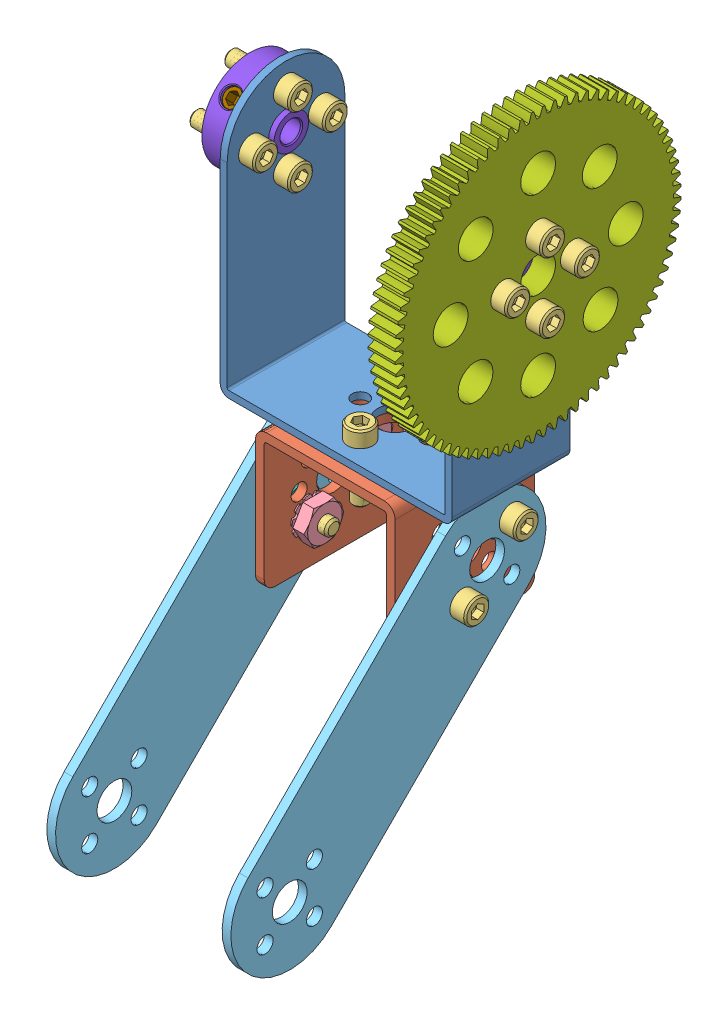
SolidWorks assembly Mantis step 13, configuration Default. Lengths in mm.
Overall size (74.01 159.73 97.13).
33 component instances, 9 part files, 97 mates.
Components (placement in the parent):
- Bracket servo_pivot_multi-1: Bracket servo_pivot_multi [Default] at origin size (53.2 60.1 27)
- Channel 32mm-1: Channel 32mm [Default] x (-1 0 0) z (0 0 1) size (32 32 32)
- Screw SHCS 6-32 x 0.5-1: Screw SHCS 6-32 x 0.5 [PreviewCfg] at (0 5.1052 8) x (0 -1 0) z (0 0 -1) size (16.21 5.74 5.74)
- Screw SHCS 6-32 x 0.5-2: Screw SHCS 6-32 x 0.5 [PreviewCfg] at (0 5.1052 -8) x (0 -1 0) z (0 0 -1) size (16.21 5.74 5.74)
- Nut Hex 6-32 KEP lock-1: Nut Hex 6-32 KEP lock [90675A007] at (0 -4.1828 8) x (-1 0 0) z (0 0 1) size (8.74 3.59 9.17)
- Nut Hex 6-32 KEP lock-2: Nut Hex 6-32 KEP lock [90675A007] at (0 -4.1828 -8) x (-1 0 0) z (0 0 1) size (8.74 3.59 9.17)
- Bracket flat-1: Bracket flat [Default] at (20.1 -38.6274 22.6274) x (0 0.707107 -0.707107) z (0 0.707107 0.707107) size (91 2 27)
- Bracket flat-2: Bracket flat [Default] at (-20.1 -38.6274 22.6274) x (0 0.707107 -0.707107) z (0 0.707107 0.707107) size (91 2 27)
- Nylon spacer small-1: Nylon spacer small [Default] at (19.1 -21.6569 5.6569) x (0 -1 0) z (1 0 0) size (9.5 9.5 3.1)
- Nylon spacer small-2: Nylon spacer small [Default] at (19.1 -10.3431 -5.6569) x (0 1 0) z (1 0 0) size (9.5 9.5 3.1)
- Nylon spacer small-3: Nylon spacer small [Default] at (-16 -10.3431 -5.6569) x (0 1 0) z (1 0 0) size (9.5 9.5 3.1)
- Nylon spacer small-4: Nylon spacer small [Default] at (-16 -21.6569 5.6569) x (0 1 0) z (1 0 0) size (9.5 9.5 3.1)
- Screw SHCS 6-32 x 0.5-3: Screw SHCS 6-32 x 0.5 [PreviewCfg] at (24.6052 -10.3431 -5.6569) x (-1 0 0) z (0 0 1) size (16.21 5.74 5.74)
- Screw SHCS 6-32 x 0.5-4: Screw SHCS 6-32 x 0.5 [PreviewCfg] at (24.6052 -21.6569 5.6569) x (-1 0 0) z (0 0 -1) size (16.21 5.74 5.74)
- Screw SHCS 6-32 x 0.5-5: Screw SHCS 6-32 x 0.5 [PreviewCfg] at (-24.6052 -10.3431 -5.6569) x (1 0 0) z (0 0 -1) size (16.21 5.74 5.74)
- Screw SHCS 6-32 x 0.5-6: Screw SHCS 6-32 x 0.5 [PreviewCfg] at (-24.6052 -21.6569 5.6569) size (16.21 5.74 5.74)
- Nut Hex 6-32 KEP lock-3: Nut Hex 6-32 KEP lock [90675A007] at (11.8172 -10.3431 -5.6569) x (0 1 0) z (0 0 1) size (8.74 3.59 9.17)
- Nut Hex 6-32 KEP lock-4: Nut Hex 6-32 KEP lock [90675A007] at (11.8172 -21.6569 5.6569) x (0 1 0) z (0 0 1) size (8.74 3.59 9.17)
- Nut Hex 6-32 KEP lock-5: Nut Hex 6-32 KEP lock [90675A007] at (-11.8172 -21.6569 5.6569) x (0 -1 0) z (0 0 1) size (8.74 3.59 9.17)
- Nut Hex 6-32 KEP lock-6: Nut Hex 6-32 KEP lock [90675A007] at (-11.8172 -10.3431 -5.6569) x (0 -1 0) z (0 0 1) size (8.74 3.59 9.17)
- Gear Metric 80T-1: Gear Metric 80T [PreviewCfg] at (26.6 46.6 0) size (6.2 65.57 65.57)
- Hub axle shaft-1: Hub axle shaft [Default] at (25 46.6 0) x (0 0 -1) z (1 0 0) size (22 22 9.5)
- Hub axle shaft-2: Hub axle shaft [Default] at (-26.6 46.6 0) x (0 0 -1) z (1 0 0) size (22 22 9.5)
- Screw SHCS 6-32 x 0.5-7: Screw SHCS 6-32 x 0.5 [PreviewCfg] at (-21.4948 54.6 0) x (-1 0 0) z (0 1 0) size (16.21 5.74 5.74)
- Screw SHCS 6-32 x 0.5-8: Screw SHCS 6-32 x 0.5 [PreviewCfg] at (-21.4948 46.6 -8) x (-1 0 0) z (0 1 0) size (16.21 5.74 5.74)
- Screw SHCS 6-32 x 0.5-9: Screw SHCS 6-32 x 0.5 [PreviewCfg] at (-21.4948 38.6 0) x (-1 0 0) z (0 1 0) size (16.21 5.74 5.74)
- Screw SHCS 6-32 x 0.5-10: Screw SHCS 6-32 x 0.5 [PreviewCfg] at (-21.4948 46.6 8) x (-1 0 0) z (0 1 0) size (16.21 5.74 5.74)
- Screw SHCS 6-32 x 0.5-13: Screw SHCS 6-32 x 0.5 [PreviewCfg] at (36.3052 54.6 0) x (-1 0 0) z (0 -1 0) size (16.21 5.74 5.74)
- Screw SHCS 6-32 x 0.5-14: Screw SHCS 6-32 x 0.5 [PreviewCfg] at (36.3052 46.6 8) x (-1 0 0) z (0 -1 0) size (16.21 5.74 5.74)
- Screw SHCS 6-32 x 0.5-15: Screw SHCS 6-32 x 0.5 [PreviewCfg] at (36.3052 38.6 0) x (-1 0 0) z (0 -1 0) size (16.21 5.74 5.74)
- Screw SHCS 6-32 x 0.5-16: Screw SHCS 6-32 x 0.5 [PreviewCfg] at (36.3052 46.6 -8) x (-1 0 0) z (0 -1 0) size (16.21 5.74 5.74)
- Screw SET 10-32 x 0.3125-1: Screw SET 10-32 x 0.3125 [PreviewCfg] at (-29.9516 53.8687 7.2793) x (0 -0.706591 -0.707622) z (0 0.707622 -0.706591) size (7.94 4.83 4.83)
- Screw SET 10-32 x 0.3125-2: Screw SET 10-32 x 0.3125 [PreviewCfg] at (21.6484 53.8687 7.2793) x (0 -0.706591 -0.707622) z (0 -0.707622 0.706591) size (7.94 4.83 4.83)
Mates (geometry in assembly coordinates):
- Coincident38: coincident anti-aligned: plane of Bracket servo_pivot_multi-1 through (-24.6 0 -13.5) normal (0 -1 0); plane of Channel 32mm-1 through (13.5 0 16) normal (0 1 0)
- Coincident39: coincident aligned: plane of Channel 32mm-1 through (0 0 0) normal (0 0 1); plane of assembly through (0 0 0) normal (0 0 1)
- Coincident40: coincident anti-aligned: plane of Channel 32mm-1; plane of assembly through (0 0 0) normal (1 0 0)
- Concentric7: concentric anti-aligned: cylinder of Screw SHCS 6-32 x 0.5-2 through (0 36.8552 -8) axis (0 1 0) radius 1.7526; cylinder of Bracket servo_pivot_multi-1 through (0 27 -8) axis (0 -1 0) radius 1.85
- Concentric8: concentric anti-aligned: cylinder of Screw SHCS 6-32 x 0.5-1 through (0 36.8552 8) axis (0 1 0) radius 1.7526; cylinder of Bracket servo_pivot_multi-1 through (0 27 8) axis (0 -1 0) radius 1.85
- Coincident4: coincident anti-aligned: plane of Bracket servo_pivot_multi-1 through (24.6 1.6 -13.5) normal (0 1 0); plane of Screw SHCS 6-32 x 0.5-2 through (-2.8702 1.6 -8) normal (0 -1 0)
- Coincident5: coincident anti-aligned: plane of Bracket servo_pivot_multi-1 through (24.6 1.6 -13.5) normal (0 1 0); plane of Screw SHCS 6-32 x 0.5-1 through (-2.8702 1.6 8) normal (0 -1 0)
- Concentric9: concentric anti-aligned: circle of Nut Hex 6-32 KEP lock-1; cylinder of Screw SHCS 6-32 x 0.5-1 through (0 36.8552 8) axis (0 1 0) radius 1.7526
- Concentric10: concentric anti-aligned: circle of Nut Hex 6-32 KEP lock-2; cylinder of Screw SHCS 6-32 x 0.5-2 through (0 36.8552 -8) axis (0 1 0) radius 1.7526
- Concentric30: concentric aligned: cylinder of Screw SHCS 6-32 x 0.5-7 through (10.2552 54.6 0) axis (1 0 0) radius 1.7526; cylinder of Hub axle shaft-2 through (-26.6 54.6 0) axis (1 0 0) radius 1.3526
- Concentric31: concentric aligned: cylinder of Screw SHCS 6-32 x 0.5-8 through (10.2552 46.6 -8) axis (1 0 0) radius 1.7526; cylinder of Hub axle shaft-2 through (-26.6 46.6 -8) axis (1 0 0) radius 1.3526
- Concentric32: concentric aligned: cylinder of Screw SHCS 6-32 x 0.5-10 through (10.2552 46.6 8) axis (1 0 0) radius 1.7526; cylinder of Hub axle shaft-2 through (-26.6 46.6 8) axis (1 0 0) radius 1.3526
- Concentric33: concentric aligned: cylinder of Screw SHCS 6-32 x 0.5-9 through (10.2552 38.6 0) axis (1 0 0) radius 1.7526; cylinder of Hub axle shaft-2 through (-26.6 38.6 0) axis (1 0 0) radius 1.3526
- Coincident24: coincident anti-aligned: plane of Bracket servo_pivot_multi-1 through (-25 2 -13.5) normal (1 0 0); plane of Screw SHCS 6-32 x 0.5-10 through (-25 46.6 10.8702) normal (-1 0 0)
- Coincident25: coincident anti-aligned: plane of Bracket servo_pivot_multi-1 through (-25 2 -13.5) normal (1 0 0); plane of Screw SHCS 6-32 x 0.5-9 through (-25 38.6 2.8702) normal (-1 0 0)
- Coincident26: coincident anti-aligned: plane of Bracket servo_pivot_multi-1 through (-25 2 -13.5) normal (1 0 0); plane of Screw SHCS 6-32 x 0.5-8 through (-25 46.6 -5.1298) normal (-1 0 0)
- Coincident27: coincident anti-aligned: plane of Bracket servo_pivot_multi-1 through (-25 2 -13.5) normal (1 0 0); plane of Screw SHCS 6-32 x 0.5-7 through (-25 54.6 2.8702) normal (-1 0 0)
- Concentric66: concentric aligned: cylinder of Gear Metric 80T-1 through (76.6001 46.6 0) axis (-1 0 0) radius 4; cylinder of Hub axle shaft-1 through (27.8 46.6 0) axis (-1 0 0) radius 3.9624
- Coincident28: coincident anti-aligned: plane of Bracket servo_pivot_multi-1 through (26.6 2 -13.5) normal (1 0 0); plane of Gear Metric 80T-1 through (26.6 46.6 0) normal (-1 0 0)
- Concentric38: concentric aligned: cylinder of Gear Metric 80T-1 through (26.6 46.6 -8) axis (1 0 0) radius 1.75; cylinder of Screw SHCS 6-32 x 0.5-16 through (68.0552 46.6 -8) axis (1 0 0) radius 1.7526
- Concentric39: concentric aligned: cylinder of Gear Metric 80T-1 through (26.6 54.6 0) axis (1 0 0) radius 1.75; cylinder of Screw SHCS 6-32 x 0.5-13 through (68.0552 54.6 0) axis (1 0 0) radius 1.7526
- Concentric40: concentric aligned: cylinder of Screw SHCS 6-32 x 0.5-14 through (68.0552 46.6 8) axis (1 0 0) radius 1.7526; cylinder of Gear Metric 80T-1 through (26.6 46.6 8) axis (1 0 0) radius 1.75
- Concentric41: concentric aligned: circle of Gear Metric 80T-1; cylinder of Screw SHCS 6-32 x 0.5-15 through (68.0552 38.6 0) axis (1 0 0) radius 1.7526
- Coincident29: coincident anti-aligned: plane of Gear Metric 80T-1 through (32.8 46.6 0) normal (1 0 0); plane of Screw SHCS 6-32 x 0.5-13 through (32.8 54.6 -2.8702) normal (-1 0 0)
- Coincident30: coincident anti-aligned: plane of Gear Metric 80T-1 through (32.8 46.6 0) normal (1 0 0); plane of Screw SHCS 6-32 x 0.5-14 through (32.8 46.6 5.1298) normal (-1 0 0)
- Coincident31: coincident anti-aligned: plane of Gear Metric 80T-1 through (32.8 46.6 0) normal (1 0 0); plane of Screw SHCS 6-32 x 0.5-16 through (32.8 46.6 -10.8702) normal (-1 0 0)
- Coincident33: coincident anti-aligned: plane of Gear Metric 80T-1 through (32.8 46.6 0) normal (1 0 0); plane of Screw SHCS 6-32 x 0.5-15 through (32.8 38.6 -2.8702) normal (-1 0 0)
- Concentric42: concentric anti-aligned: cylinder of Hub axle shaft-2 through (-23.8 46.6 0) axis (-1 0 0) radius 3.9624; cylinder of Bracket servo_pivot_multi-1 through (-26.6 46.6 0) axis (1 0 0) radius 4
- Coincident34: coincident anti-aligned: plane of Bracket servo_pivot_multi-1 through (-26.6 60.1 -13.5) normal (-1 0 0); plane of Hub axle shaft-2 through (-26.6 46.6 0) normal (1 0 0)
- Parallel18: parallel aligned: plane of Hub axle shaft-2; plane of assembly through (0 0 0) normal (0 1 0)
- Concentric65: concentric anti-aligned: cylinder of Bracket servo_pivot_multi-1 through (-26.6 46.6 0) axis (1 0 0) radius 4; cylinder of Hub axle shaft-1 through (27.8 46.6 0) axis (-1 0 0) radius 3.9624
- Coincident35: coincident anti-aligned: plane of Bracket servo_pivot_multi-1 through (25 60.1 -13.5) normal (-1 0 0); plane of Hub axle shaft-1 through (25 46.6 0) normal (1 0 0)
- Parallel17: parallel aligned: plane of Hub axle shaft-1; plane of assembly through (0 0 0) normal (0 1 0)
- Concentric44: concentric aligned: cylinder of Screw SET 10-32 x 0.3125-2 through (21.6484 62.8424 16.2661) axis (0 0.706591 0.707622) radius 2.413; cylinder of Hub axle shaft-1 through (21.6484 54.3725 7.7838) axis (0 0.706591 0.707622) radius 2.0193
- Concentric45: concentric aligned: cylinder of Screw SET 10-32 x 0.3125-1 through (-29.9516 62.8424 16.2661) axis (0 0.706591 0.707622) radius 2.413; cylinder of Hub axle shaft-2 through (-29.9516 54.3725 7.7838) axis (0 0.706591 0.707622) radius 2.0193
- Concentric48: concentric anti-aligned: cylinder of Screw SHCS 6-32 x 0.5-10 through (10.2552 46.6 8) axis (1 0 0) radius 1.7526; circle of Hub axle shaft-1
- Coincident41: coincident aligned: plane of Channel 32mm-1 through (-13.5 -2 16) normal (0 -1 0); plane of Nut Hex 6-32 KEP lock-2
- Coincident42: coincident aligned: plane of Channel 32mm-1 through (-13.5 -2 16) normal (0 -1 0); plane of Nut Hex 6-32 KEP lock-1
- Parallel1: parallel anti-aligned: plane of assembly through (0 0 0) normal (1 0 0); plane of Nut Hex 6-32 KEP lock-2
- Parallel2: parallel anti-aligned: plane of assembly through (0 0 0) normal (1 0 0); plane of Nut Hex 6-32 KEP lock-1
- Parallel3: parallel anti-aligned: plane of assembly through (0 0 0) normal (1 0 0); plane of Screw SHCS 6-32 x 0.5-2
- Parallel4: parallel anti-aligned: plane of assembly through (0 0 0) normal (1 0 0); plane of Screw SHCS 6-32 x 0.5-1
- Concentric49: concentric anti-aligned: cylinder of Channel 32mm-1 through (-16 -16 0) axis (1 0 0) radius 4; cylinder of Bracket flat-2 through (-19.1 -16 0) axis (-1 0 0) radius 4
- Concentric50: concentric anti-aligned: cylinder of Channel 32mm-1 through (-16 -16 0) axis (1 0 0) radius 4; cylinder of Bracket flat-1 through (21.1 -16 0) axis (-1 0 0) radius 4
- Concentric51: concentric aligned: cylinder of Channel 32mm-1 through (-16 -10.3431 -5.6569) axis (1 0 0) radius 1.85; cylinder of Nylon spacer small-2 through (16 -10.3431 -5.6569) axis (1 0 0) radius 2.5
- Coincident43: coincident anti-aligned: plane of Nylon spacer small-2 through (16 -10.3431 -5.6569) normal (-1 0 0); plane of Channel 32mm-1 through (16 -32 16) normal (1 0 0)
- Concentric52: concentric aligned: cylinder of Channel 32mm-1 through (-16 -21.6569 5.6569) axis (1 0 0) radius 1.85; cylinder of Nylon spacer small-1 through (16 -21.6569 5.6569) axis (1 0 0) radius 2.5
- Coincident44: coincident anti-aligned: plane of Nylon spacer small-1 through (16 -21.6569 5.6569) normal (-1 0 0); plane of Channel 32mm-1 through (16 -32 16) normal (1 0 0)
- Concentric53: concentric aligned: cylinder of Nylon spacer small-3 through (-19.1 -10.3431 -5.6569) axis (1 0 0) radius 2.5; cylinder of Channel 32mm-1 through (-16 -10.3431 -5.6569) axis (1 0 0) radius 1.85
- Coincident46: coincident anti-aligned: plane of Channel 32mm-1 through (-16 -2.5 16) normal (-1 0 0); plane of Nylon spacer small-3 through (-16 -10.3431 -5.6569) normal (1 0 0)
- Concentric54: concentric aligned: cylinder of Channel 32mm-1 through (-16 -21.6569 5.6569) axis (1 0 0) radius 1.85; cylinder of Nylon spacer small-4 through (-19.1 -21.6569 5.6569) axis (1 0 0) radius 2.5
- Coincident47: coincident anti-aligned: plane of Channel 32mm-1 through (-16 -2.5 16) normal (-1 0 0); plane of Nylon spacer small-4 through (-16 -21.6569 5.6569) normal (1 0 0)
- Concentric55: concentric anti-aligned: cylinder of Channel 32mm-1 through (-16 -10.3431 -5.6569) axis (1 0 0) radius 1.85; cylinder of Bracket flat-1 through (21.1 -10.3431 -5.6569) axis (-1 0 0) radius 1.85
- Coincident48: coincident anti-aligned: plane of Bracket flat-1 through (19.1 -80.3467 45.2548) normal (-1 0 0); plane of Nylon spacer small-2 through (19.1 -10.3431 -5.6569) normal (1 0 0)
- Concentric56: concentric anti-aligned: cylinder of Channel 32mm-1 through (-16 -10.3431 -5.6569) axis (1 0 0) radius 1.85; cylinder of Bracket flat-2 through (-19.1 -10.3431 -5.6569) axis (-1 0 0) radius 1.85
- Coincident49: coincident anti-aligned: plane of Bracket flat-2 through (-19.1 -80.3467 45.2548) normal (1 0 0); plane of Nylon spacer small-3 through (-19.1 -10.3431 -5.6569) normal (-1 0 0)
- Concentric57: concentric anti-aligned: cylinder of Bracket flat-1 through (21.1 -10.3431 -5.6569) axis (-1 0 0) radius 1.85; cylinder of Screw SHCS 6-32 x 0.5-3 through (56.3552 -10.3431 -5.6569) axis (1 0 0) radius 1.7526
- Coincident50: coincident anti-aligned: plane of Bracket flat-1 through (21.1 -80.3467 45.2548) normal (1 0 0); plane of Screw SHCS 6-32 x 0.5-3 through (21.1 -13.2133 -5.6569) normal (-1 0 0)
- Concentric58: concentric anti-aligned: cylinder of Bracket flat-1 through (21.1 -21.6569 5.6569) axis (-1 0 0) radius 1.85; cylinder of Screw SHCS 6-32 x 0.5-4 through (56.3552 -21.6569 5.6569) axis (1 0 0) radius 1.7526
- Coincident51: coincident anti-aligned: plane of Bracket flat-1 through (21.1 -80.3467 45.2548) normal (1 0 0); plane of Screw SHCS 6-32 x 0.5-4 through (21.1 -18.7867 5.6569) normal (-1 0 0)
- Concentric59: concentric aligned: cylinder of Bracket flat-2 through (-19.1 -10.3431 -5.6569) axis (-1 0 0) radius 1.85; cylinder of Screw SHCS 6-32 x 0.5-5 through (-56.3552 -10.3431 -5.6569) axis (-1 0 0) radius 1.7526
- Concentric60: concentric aligned: cylinder of Bracket flat-2 through (-19.1 -21.6569 5.6569) axis (-1 0 0) radius 1.85; cylinder of Screw SHCS 6-32 x 0.5-6 through (-56.3552 -21.6569 5.6569) axis (-1 0 0) radius 1.7526
- Coincident52: coincident anti-aligned: plane of Bracket flat-2 through (-21.1 -80.3467 45.2548) normal (-1 0 0); plane of Screw SHCS 6-32 x 0.5-5 through (-21.1 -13.2133 -5.6569) normal (1 0 0)
- Coincident53: coincident anti-aligned: plane of Bracket flat-2 through (-21.1 -80.3467 45.2548) normal (-1 0 0); plane of Screw SHCS 6-32 x 0.5-6 through (-21.1 -18.7867 5.6569) normal (1 0 0)
- Coincident54: coincident aligned: plane of Channel 32mm-1 through (-14 -32 16) normal (1 0 0); plane of Nut Hex 6-32 KEP lock-6
- Coincident55: coincident aligned: plane of Channel 32mm-1 through (-14 -32 16) normal (1 0 0); plane of Nut Hex 6-32 KEP lock-5
- Concentric61: concentric anti-aligned: circle of Channel 32mm-1; circle of Nut Hex 6-32 KEP lock-5
- Concentric62: concentric anti-aligned: circle of Channel 32mm-1; circle of Nut Hex 6-32 KEP lock-6
- Concentric63: concentric anti-aligned: circle of Channel 32mm-1; circle of Nut Hex 6-32 KEP lock-4
- Concentric64: concentric anti-aligned: circle of Channel 32mm-1; circle of Nut Hex 6-32 KEP lock-3
- Coincident56: coincident aligned: plane of Channel 32mm-1 through (14 -2.5 16) normal (-1 0 0); plane of Nut Hex 6-32 KEP lock-4
- Coincident57: coincident aligned: plane of Channel 32mm-1 through (14 -2.5 16) normal (-1 0 0); plane of Nut Hex 6-32 KEP lock-3
- Parallel5: parallel anti-aligned: plane of assembly through (0 0 0) normal (0 1 0); plane of Nut Hex 6-32 KEP lock-6
- Parallel6: parallel anti-aligned: plane of assembly through (0 0 0) normal (0 1 0); plane of Nut Hex 6-32 KEP lock-5
- Parallel7: parallel aligned: plane of assembly through (0 0 0) normal (0 1 0); plane of Nut Hex 6-32 KEP lock-4
- Parallel8: parallel aligned: plane of assembly through (0 0 0) normal (0 1 0); plane of Nut Hex 6-32 KEP lock-3
- Parallel9: parallel aligned: plane of assembly through (0 0 0) normal (0 1 0); plane of Screw SHCS 6-32 x 0.5-6 through (-24.6052 -21.6569 5.6569) normal (0 1 0)
- Parallel10: parallel anti-aligned: plane of assembly through (0 0 0) normal (0 1 0); plane of Screw SHCS 6-32 x 0.5-5 through (-24.6052 -10.3431 -5.6569) normal (0 -1 0)
- Parallel11: parallel aligned: plane of assembly through (0 0 0) normal (0 1 0); plane of Screw SHCS 6-32 x 0.5-4
- Parallel12: parallel anti-aligned: plane of assembly through (0 0 0) normal (0 1 0); plane of Screw SHCS 6-32 x 0.5-3
- Parallel13: parallel aligned: plane of assembly through (0 0 0) normal (0 1 0); plane of Nylon spacer small-4
- Parallel14: parallel aligned: plane of assembly through (0 0 0) normal (0 1 0); plane of Nylon spacer small-3
- Parallel15: parallel aligned: plane of assembly through (0 0 0) normal (0 1 0); plane of Nylon spacer small-2
- Parallel16: parallel anti-aligned: plane of assembly through (0 0 0) normal (0 1 0); plane of Nylon spacer small-1
- Coincident59: coincident: cylinder of Hub axle shaft-2 through (-33.3 46.6 0) axis (1 0 0) radius 2.3495; point of Screw SET 10-32 x 0.3125-1
- Coincident60: coincident: cylinder of Hub axle shaft-1 through (18.3 46.6 0) axis (1 0 0) radius 2.3495; point of Screw SET 10-32 x 0.3125-2
- Parallel19: parallel anti-aligned: plane of Screw SET 10-32 x 0.3125-1; plane of assembly through (0 0 0) normal (1 0 0)
- Parallel20: parallel aligned: plane of Screw SET 10-32 x 0.3125-2; plane of assembly through (0 0 0) normal (1 0 0)
- Parallel21: parallel anti-aligned: plane of assembly through (0 0 0) normal (0 0 1); plane of Screw SHCS 6-32 x 0.5-16
- Parallel22: parallel anti-aligned: plane of assembly through (0 0 0) normal (0 0 1); plane of Screw SHCS 6-32 x 0.5-15
- Parallel23: parallel anti-aligned: plane of assembly through (0 0 0) normal (0 0 1); plane of Screw SHCS 6-32 x 0.5-14
- Parallel24: parallel anti-aligned: plane of assembly through (0 0 0) normal (0 0 1); plane of Screw SHCS 6-32 x 0.5-13
- Parallel25: parallel aligned: plane of assembly through (0 0 0) normal (0 0 1); plane of Screw SHCS 6-32 x 0.5-10
- Parallel26: parallel aligned: plane of assembly through (0 0 0) normal (0 0 1); plane of Screw SHCS 6-32 x 0.5-9
- Parallel27: parallel aligned: plane of assembly through (0 0 0) normal (0 0 1); plane of Screw SHCS 6-32 x 0.5-8
- Parallel28: parallel aligned: plane of assembly through (0 0 0) normal (0 0 1); plane of Screw SHCS 6-32 x 0.5-7
- Concentric69: concentric aligned: cylinder of Bracket servo_pivot_multi-1 through (-26.6 54.6 0) axis (1 0 0) radius 1.85; cylinder of Screw SHCS 6-32 x 0.5-13 through (68.0552 54.6 0) axis (1 0 0) radius 1.7526
